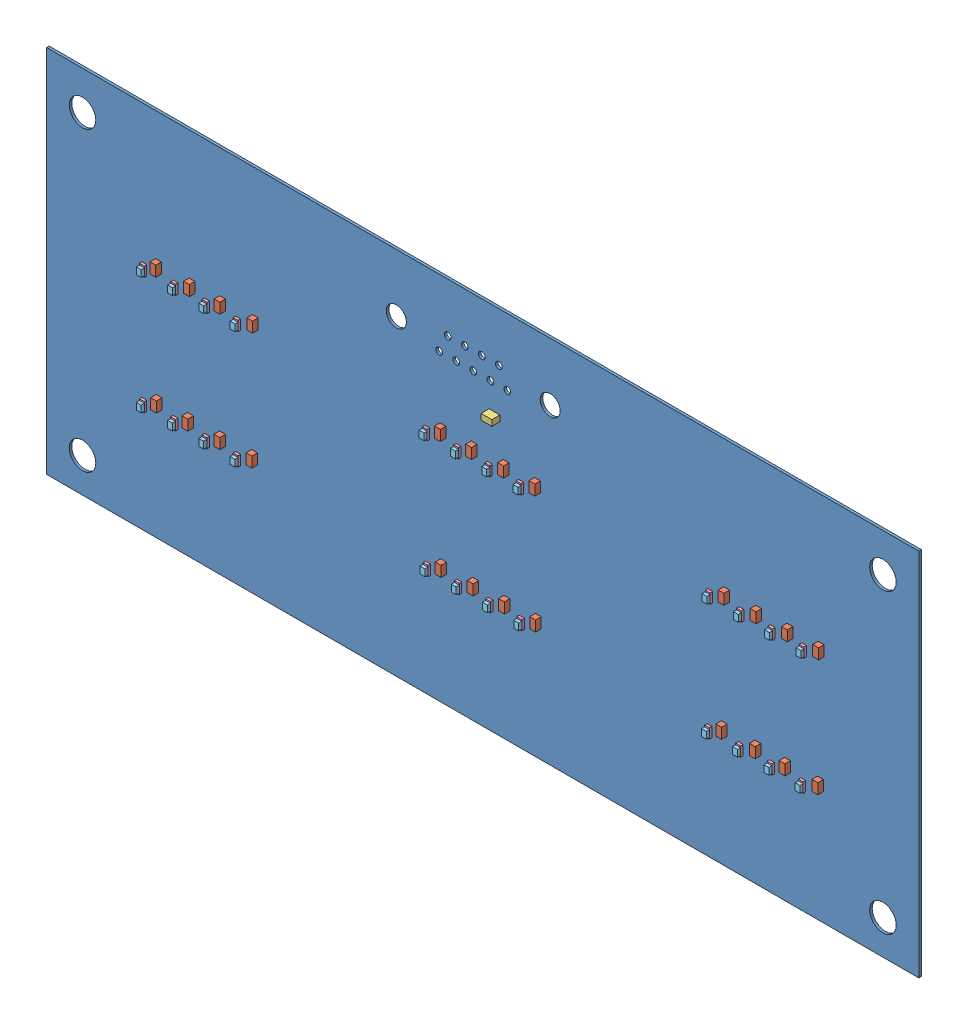
SolidWorks assembly FEV-60_LED_Panel3, configuration Default. Lengths in mm.
Overall size (141.73 60.07 1.71).
198 component instances, 5 part files, 0 mates.
Components (placement in the parent):
- FEV-60_LED_Panel.step-1: FEV-60_LED_Panel.step [Default] at origin size (141.73 60.07 1.71)
  - Board.step-1: Board.step [Default] at origin size (141.73 60.07 0.41)
    - Open CASCADE STEP translator 6.8 3.1.1.step-1: Open CASCADE STEP translator 6.8 3.1.1.step [Default] at (0 0 -0.4115) size (141.73 60.07 0.41)
  - R24.step-1: R24.step [Default] at origin size (0.95 1.7 0.9)
    - 6216516608.step-1: 6216516608.step [Default] at (135.509 74.676 0) size (0.95 1.7 0.9)
      - Extruded.step-1: Extruded.step [Default] at origin size (0.95 1.7 0.9)
  - R23.step-1: R23.step [Default] at origin size (0.95 1.7 0.9)
    - 6216516608.step-1: 6216516608.step [Default] at (89.916 74.664 0) size (0.95 1.7 0.9)
      - Extruded.step-1: Extruded.step [Default] at origin size (0.95 1.7 0.9)
  - R22.step-1: R22.step [Default] at origin size (0.95 1.7 0.9)
    - 6216516608.step-1: 6216516608.step [Default] at (43.688 74.676 0) size (0.95 1.7 0.9)
      - Extruded.step-1: Extruded.step [Default] at origin size (0.95 1.7 0.9)
  - R21.step-1: R21.step [Default] at origin size (0.95 1.7 0.9)
    - 6216516608.step-1: 6216516608.step [Default] at (140.97 74.676 0) size (0.95 1.7 0.9)
      - Extruded.step-1: Extruded.step [Default] at origin size (0.95 1.7 0.9)
  - R20.step-1: R20.step [Default] at origin size (0.95 1.7 0.9)
    - 6216516608.step-1: 6216516608.step [Default] at (95.123 74.664 0) size (0.95 1.7 0.9)
      - Extruded.step-1: Extruded.step [Default] at origin size (0.95 1.7 0.9)
  - R19.step-1: R19.step [Default] at origin size (0.95 1.7 0.9)
    - 6216516608.step-1: 6216516608.step [Default] at (48.768 74.676 0) size (0.95 1.7 0.9)
      - Extruded.step-1: Extruded.step [Default] at origin size (0.95 1.7 0.9)
  - R18.step-1: R18.step [Default] at origin size (0.95 1.7 0.9)
    - 6216516608.step-1: 6216516608.step [Default] at (145.796 74.676 0) size (0.95 1.7 0.9)
      - Extruded.step-1: Extruded.step [Default] at origin size (0.95 1.7 0.9)
  - R17.step-1: R17.step [Default] at origin size (0.95 1.7 0.9)
    - 6216516608.step-1: 6216516608.step [Default] at (100.203 74.664 0) size (0.95 1.7 0.9)
      - Extruded.step-1: Extruded.step [Default] at origin size (0.95 1.7 0.9)
  - R16.step-1: R16.step [Default] at origin size (0.95 1.7 0.9)
    - 6216516608.step-1: 6216516608.step [Default] at (53.975 74.676 0) size (0.95 1.7 0.9)
      - Extruded.step-1: Extruded.step [Default] at origin size (0.95 1.7 0.9)
  - R15.step-1: R15.step [Default] at origin size (0.95 1.7 0.9)
    - 6216516608.step-1: 6216516608.step [Default] at (151.13 74.688 0) size (0.95 1.7 0.9)
      - Extruded.step-1: Extruded.step [Default] at origin size (0.95 1.7 0.9)
  - R14.step-1: R14.step [Default] at origin size (0.95 1.7 0.9)
    - 6216516608.step-1: 6216516608.step [Default] at (105.283 74.664 0) size (0.95 1.7 0.9)
      - Extruded.step-1: Extruded.step [Default] at origin size (0.95 1.7 0.9)
  - R13.step-1: R13.step [Default] at origin size (0.95 1.7 0.9)
    - 6216516608.step-1: 6216516608.step [Default] at (59.182 74.676 0) size (0.95 1.7 0.9)
      - Extruded.step-1: Extruded.step [Default] at origin size (0.95 1.7 0.9)
  - R12.step-1: R12.step [Default] at origin size (0.95 1.7 0.9)
    - 6216516608.step-1: 6216516608.step [Default] at (135.89 93.726 0) size (0.95 1.7 0.9)
      - Extruded.step-1: Extruded.step [Default] at origin size (0.95 1.7 0.9)
  - R11.step-1: R11.step [Default] at origin size (0.95 1.7 0.9)
    - 6216516608.step-1: 6216516608.step [Default] at (89.789 93.726 0) size (0.95 1.7 0.9)
      - Extruded.step-1: Extruded.step [Default] at origin size (0.95 1.7 0.9)
  - R10.step-1: R10.step [Default] at origin size (0.95 1.7 0.9)
    - 6216516608.step-1: 6216516608.step [Default] at (43.561 93.726 0) size (0.95 1.7 0.9)
      - Extruded.step-1: Extruded.step [Default] at origin size (0.95 1.7 0.9)
  - R9.step-1: R9.step [Default] at origin size (0.95 1.7 0.9)
    - 6216516608.step-1: 6216516608.step [Default] at (141.097 93.726 0) size (0.95 1.7 0.9)
      - Extruded.step-1: Extruded.step [Default] at origin size (0.95 1.7 0.9)
  - R8.step-1: R8.step [Default] at origin size (0.95 1.7 0.9)
    - 6216516608.step-1: 6216516608.step [Default] at (94.869 93.726 0) size (0.95 1.7 0.9)
      - Extruded.step-1: Extruded.step [Default] at origin size (0.95 1.7 0.9)
  - R7.step-1: R7.step [Default] at origin size (0.95 1.7 0.9)
    - 6216516608.step-1: 6216516608.step [Default] at (49.022 93.726 0) size (0.95 1.7 0.9)
      - Extruded.step-1: Extruded.step [Default] at origin size (0.95 1.7 0.9)
  - R6.step-1: R6.step [Default] at origin size (0.95 1.7 0.9)
    - 6216516608.step-1: 6216516608.step [Default] at (146.177 93.726 0) size (0.95 1.7 0.9)
      - Extruded.step-1: Extruded.step [Default] at origin size (0.95 1.7 0.9)
  - R5.step-1: R5.step [Default] at origin size (0.95 1.7 0.9)
    - 6216516608.step-1: 6216516608.step [Default] at (100.076 93.726 0) size (0.95 1.7 0.9)
      - Extruded.step-1: Extruded.step [Default] at origin size (0.95 1.7 0.9)
  - R4.step-1: R4.step [Default] at origin size (0.95 1.7 0.9)
    - 6216516608.step-1: 6216516608.step [Default] at (53.975 93.726 0) size (0.95 1.7 0.9)
      - Extruded.step-1: Extruded.step [Default] at origin size (0.95 1.7 0.9)
  - R3.step-1: R3.step [Default] at origin size (0.95 1.7 0.9)
    - 6216516608.step-1: 6216516608.step [Default] at (151.257 93.726 0) size (0.95 1.7 0.9)
      - Extruded.step-1: Extruded.step [Default] at origin size (0.95 1.7 0.9)
  - R2.step-1: R2.step [Default] at origin size (0.95 1.7 0.9)
    - 6216516608.step-1: 6216516608.step [Default] at (105.156 93.726 0) size (0.95 1.7 0.9)
      - Extruded.step-1: Extruded.step [Default] at origin size (0.95 1.7 0.9)
  - C1.step-1: C1.step [Default] at origin size (1.75 0.95 1.3)
    - 6216520128.step-1: 6216520128.step [Default] at (98.171 100.076 0) size (1.75 0.95 1.3)
      - Extruded-0.step-1: Extruded-0.step [Default] at origin size (1.75 0.95 1.3)
  - R1.step-1: R1.step [Default] at origin size (0.95 1.7 0.9)
    - 6216516608.step-1: 6216516608.step [Default] at (59.309 93.726 0) size (0.95 1.7 0.9)
      - Extruded.step-1: Extruded.step [Default] at origin size (0.95 1.7 0.9)
  - DS24.step-1: DS24.step [Default] at origin size (0.8 1.6 0.9)
    - 6363329008.step-1: 6363329008.step [Default] at (133.0958 73.1522 0) size (0.8 1.6 0.4)
      - Extruded-1.step-1: Extruded-1.step [Default] at origin size (0.8 1.6 0.4)
    - 6363328768.step-1: 6363328768.step [Default] at (133.0958 73.1522 0.4) size (0.8 1.1 0.5)
      - Extruded-2.step-1: Extruded-2.step [Default] at origin size (0.8 1.1 0.5)
  - DS23.step-1: DS23.step [Default] at origin size (0.8 1.6 0.9)
    - 6363329008.step-1: 6363329008.step [Default] at (87.3759 73.1521 0) size (0.8 1.6 0.4)
      - Extruded-1.step-1: Extruded-1.step [Default] at origin size (0.8 1.6 0.4)
    - 6363328768.step-1: 6363328768.step [Default] at (87.3759 73.1521 0.4) size (0.8 1.1 0.5)
      - Extruded-2.step-1: Extruded-2.step [Default] at origin size (0.8 1.1 0.5)
  - DS22.step-1: DS22.step [Default] at origin size (0.8 1.6 0.9)
    - 6363329008.step-1: 6363329008.step [Default] at (41.2749 73.1521 0) size (0.8 1.6 0.4)
      - Extruded-1.step-1: Extruded-1.step [Default] at origin size (0.8 1.6 0.4)
    - 6363328768.step-1: 6363328768.step [Default] at (41.2749 73.1521 0.4) size (0.8 1.1 0.5)
      - Extruded-2.step-1: Extruded-2.step [Default] at origin size (0.8 1.1 0.5)
  - DS21.step-1: DS21.step [Default] at origin size (0.8 1.6 0.9)
    - 6363329008.step-1: 6363329008.step [Default] at (138.1758 73.1522 0) size (0.8 1.6 0.4)
      - Extruded-1.step-1: Extruded-1.step [Default] at origin size (0.8 1.6 0.4)
    - 6363328768.step-1: 6363328768.step [Default] at (138.1758 73.1522 0.4) size (0.8 1.1 0.5)
      - Extruded-2.step-1: Extruded-2.step [Default] at origin size (0.8 1.1 0.5)
  - DS20.step-1: DS20.step [Default] at origin size (0.8 1.6 0.9)
    - 6363329008.step-1: 6363329008.step [Default] at (92.4559 73.1521 0) size (0.8 1.6 0.4)
      - Extruded-1.step-1: Extruded-1.step [Default] at origin size (0.8 1.6 0.4)
    - 6363328768.step-1: 6363328768.step [Default] at (92.4559 73.1521 0.4) size (0.8 1.1 0.5)
      - Extruded-2.step-1: Extruded-2.step [Default] at origin size (0.8 1.1 0.5)
  - DS19.step-1: DS19.step [Default] at origin size (0.8 1.6 0.9)
    - 6363329008.step-1: 6363329008.step [Default] at (46.3549 73.1521 0) size (0.8 1.6 0.4)
      - Extruded-1.step-1: Extruded-1.step [Default] at origin size (0.8 1.6 0.4)
    - 6363328768.step-1: 6363328768.step [Default] at (46.3549 73.1521 0.4) size (0.8 1.1 0.5)
      - Extruded-2.step-1: Extruded-2.step [Default] at origin size (0.8 1.1 0.5)
  - DS18.step-1: DS18.step [Default] at origin size (0.8 1.6 0.9)
    - 6363329008.step-1: 6363329008.step [Default] at (143.2558 73.1522 0) size (0.8 1.6 0.4)
      - Extruded-1.step-1: Extruded-1.step [Default] at origin size (0.8 1.6 0.4)
    - 6363328768.step-1: 6363328768.step [Default] at (143.2558 73.1522 0.4) size (0.8 1.1 0.5)
      - Extruded-2.step-1: Extruded-2.step [Default] at origin size (0.8 1.1 0.5)
  - DS17.step-1: DS17.step [Default] at origin size (0.8 1.6 0.9)
    - 6363329008.step-1: 6363329008.step [Default] at (97.5359 73.1521 0) size (0.8 1.6 0.4)
      - Extruded-1.step-1: Extruded-1.step [Default] at origin size (0.8 1.6 0.4)
    - 6363328768.step-1: 6363328768.step [Default] at (97.5359 73.1521 0.4) size (0.8 1.1 0.5)
      - Extruded-2.step-1: Extruded-2.step [Default] at origin size (0.8 1.1 0.5)
  - DS16.step-1: DS16.step [Default] at origin size (0.8 1.6 0.9)
    - 6363329008.step-1: 6363329008.step [Default] at (51.4349 73.1521 0) size (0.8 1.6 0.4)
      - Extruded-1.step-1: Extruded-1.step [Default] at origin size (0.8 1.6 0.4)
    - 6363328768.step-1: 6363328768.step [Default] at (51.4349 73.1521 0.4) size (0.8 1.1 0.5)
      - Extruded-2.step-1: Extruded-2.step [Default] at origin size (0.8 1.1 0.5)
  - DS15.step-1: DS15.step [Default] at origin size (0.8 1.6 0.9)
    - 6363329008.step-1: 6363329008.step [Default] at (148.3358 73.1522 0) size (0.8 1.6 0.4)
      - Extruded-1.step-1: Extruded-1.step [Default] at origin size (0.8 1.6 0.4)
    - 6363328768.step-1: 6363328768.step [Default] at (148.3358 73.1522 0.4) size (0.8 1.1 0.5)
      - Extruded-2.step-1: Extruded-2.step [Default] at origin size (0.8 1.1 0.5)
  - DS14.step-1: DS14.step [Default] at origin size (0.8 1.6 0.9)
    - 6363329008.step-1: 6363329008.step [Default] at (102.6159 73.1521 0) size (0.8 1.6 0.4)
      - Extruded-1.step-1: Extruded-1.step [Default] at origin size (0.8 1.6 0.4)
    - 6363328768.step-1: 6363328768.step [Default] at (102.6159 73.1521 0.4) size (0.8 1.1 0.5)
      - Extruded-2.step-1: Extruded-2.step [Default] at origin size (0.8 1.1 0.5)
  - DS13.step-1: DS13.step [Default] at origin size (0.8 1.6 0.9)
    - 6363329008.step-1: 6363329008.step [Default] at (56.5149 73.1521 0) size (0.8 1.6 0.4)
      - Extruded-1.step-1: Extruded-1.step [Default] at origin size (0.8 1.6 0.4)
    - 6363328768.step-1: 6363328768.step [Default] at (56.5149 73.1521 0.4) size (0.8 1.1 0.5)
      - Extruded-2.step-1: Extruded-2.step [Default] at origin size (0.8 1.1 0.5)
  - DS12.step-1: DS12.step [Default] at origin size (0.8 1.6 0.9)
    - 6363329008.step-1: 6363329008.step [Default] at (133.2228 92.2022 0) size (0.8 1.6 0.4)
      - Extruded-1.step-1: Extruded-1.step [Default] at origin size (0.8 1.6 0.4)
    - 6363328768.step-1: 6363328768.step [Default] at (133.2228 92.2022 0.4) size (0.8 1.1 0.5)
      - Extruded-2.step-1: Extruded-2.step [Default] at origin size (0.8 1.1 0.5)
  - DS11.step-1: DS11.step [Default] at origin size (0.8 1.6 0.9)
    - 6363329008.step-1: 6363329008.step [Default] at (87.249 92.214 0) size (0.8 1.6 0.4)
      - Extruded-1.step-1: Extruded-1.step [Default] at origin size (0.8 1.6 0.4)
    - 6363328768.step-1: 6363328768.step [Default] at (87.249 92.214 0.4) size (0.8 1.1 0.5)
      - Extruded-2.step-1: Extruded-2.step [Default] at origin size (0.8 1.1 0.5)
  - DS10.step-1: DS10.step [Default] at origin size (0.8 1.6 0.9)
    - 6363329008.step-1: 6363329008.step [Default] at (41.275 92.214 0) size (0.8 1.6 0.4)
      - Extruded-1.step-1: Extruded-1.step [Default] at origin size (0.8 1.6 0.4)
    - 6363328768.step-1: 6363328768.step [Default] at (41.275 92.214 0.4) size (0.8 1.1 0.5)
      - Extruded-2.step-1: Extruded-2.step [Default] at origin size (0.8 1.1 0.5)
  - DS9.step-1: DS9.step [Default] at origin size (0.8 1.6 0.9)
    - 6363329008.step-1: 6363329008.step [Default] at (138.3028 92.2022 0) size (0.8 1.6 0.4)
      - Extruded-1.step-1: Extruded-1.step [Default] at origin size (0.8 1.6 0.4)
    - 6363328768.step-1: 6363328768.step [Default] at (138.3028 92.2022 0.4) size (0.8 1.1 0.5)
      - Extruded-2.step-1: Extruded-2.step [Default] at origin size (0.8 1.1 0.5)
  - DS8.step-1: DS8.step [Default] at origin size (0.8 1.6 0.9)
    - 6363329008.step-1: 6363329008.step [Default] at (92.3289 92.2021 0) size (0.8 1.6 0.4)
      - Extruded-1.step-1: Extruded-1.step [Default] at origin size (0.8 1.6 0.4)
    - 6363328768.step-1: 6363328768.step [Default] at (92.3289 92.2021 0.4) size (0.8 1.1 0.5)
      - Extruded-2.step-1: Extruded-2.step [Default] at origin size (0.8 1.1 0.5)
  - DS7.step-1: DS7.step [Default] at origin size (0.8 1.6 0.9)
    - 6363329008.step-1: 6363329008.step [Default] at (46.3549 92.2021 0) size (0.8 1.6 0.4)
      - Extruded-1.step-1: Extruded-1.step [Default] at origin size (0.8 1.6 0.4)
    - 6363328768.step-1: 6363328768.step [Default] at (46.3549 92.2021 0.4) size (0.8 1.1 0.5)
      - Extruded-2.step-1: Extruded-2.step [Default] at origin size (0.8 1.1 0.5)
  - DS6.step-1: DS6.step [Default] at origin size (0.8 1.6 0.9)
    - 6363329008.step-1: 6363329008.step [Default] at (143.3828 92.2022 0) size (0.8 1.6 0.4)
      - Extruded-1.step-1: Extruded-1.step [Default] at origin size (0.8 1.6 0.4)
    - 6363328768.step-1: 6363328768.step [Default] at (143.3828 92.2022 0.4) size (0.8 1.1 0.5)
      - Extruded-2.step-1: Extruded-2.step [Default] at origin size (0.8 1.1 0.5)
  - DS5.step-1: DS5.step [Default] at origin size (0.8 1.6 0.9)
    - 6363329008.step-1: 6363329008.step [Default] at (97.4089 92.2021 0) size (0.8 1.6 0.4)
      - Extruded-1.step-1: Extruded-1.step [Default] at origin size (0.8 1.6 0.4)
    - 6363328768.step-1: 6363328768.step [Default] at (97.4089 92.2021 0.4) size (0.8 1.1 0.5)
      - Extruded-2.step-1: Extruded-2.step [Default] at origin size (0.8 1.1 0.5)
  - DS4.step-1: DS4.step [Default] at origin size (0.8 1.6 0.9)
    - 6363329008.step-1: 6363329008.step [Default] at (51.4349 92.2021 0) size (0.8 1.6 0.4)
      - Extruded-1.step-1: Extruded-1.step [Default] at origin size (0.8 1.6 0.4)
    - 6363328768.step-1: 6363328768.step [Default] at (51.4349 92.2021 0.4) size (0.8 1.1 0.5)
      - Extruded-2.step-1: Extruded-2.step [Default] at origin size (0.8 1.1 0.5)
  - DS3.step-1: DS3.step [Default] at origin size (0.8 1.6 0.9)
    - 6363329008.step-1: 6363329008.step [Default] at (148.4628 92.2022 0) size (0.8 1.6 0.4)
      - Extruded-1.step-1: Extruded-1.step [Default] at origin size (0.8 1.6 0.4)
    - 6363328768.step-1: 6363328768.step [Default] at (148.4628 92.2022 0.4) size (0.8 1.1 0.5)
      - Extruded-2.step-1: Extruded-2.step [Default] at origin size (0.8 1.1 0.5)
  - DS2.step-1: DS2.step [Default] at origin size (0.8 1.6 0.9)
    - 6363329008.step-1: 6363329008.step [Default] at (102.4889 92.2021 0) size (0.8 1.6 0.4)
      - Extruded-1.step-1: Extruded-1.step [Default] at origin size (0.8 1.6 0.4)
    - 6363328768.step-1: 6363328768.step [Default] at (102.4889 92.2021 0.4) size (0.8 1.1 0.5)
      - Extruded-2.step-1: Extruded-2.step [Default] at origin size (0.8 1.1 0.5)
  - DS1.step-1: DS1.step [Default] at origin size (0.8 1.6 0.9)
    - 6363329008.step-1: 6363329008.step [Default] at (56.5149 92.2021 0) size (0.8 1.6 0.4)
      - Extruded-1.step-1: Extruded-1.step [Default] at origin size (0.8 1.6 0.4)
    - 6363328768.step-1: 6363328768.step [Default] at (56.5149 92.2021 0.4) size (0.8 1.1 0.5)
      - Extruded-2.step-1: Extruded-2.step [Default] at origin size (0.8 1.1 0.5)
